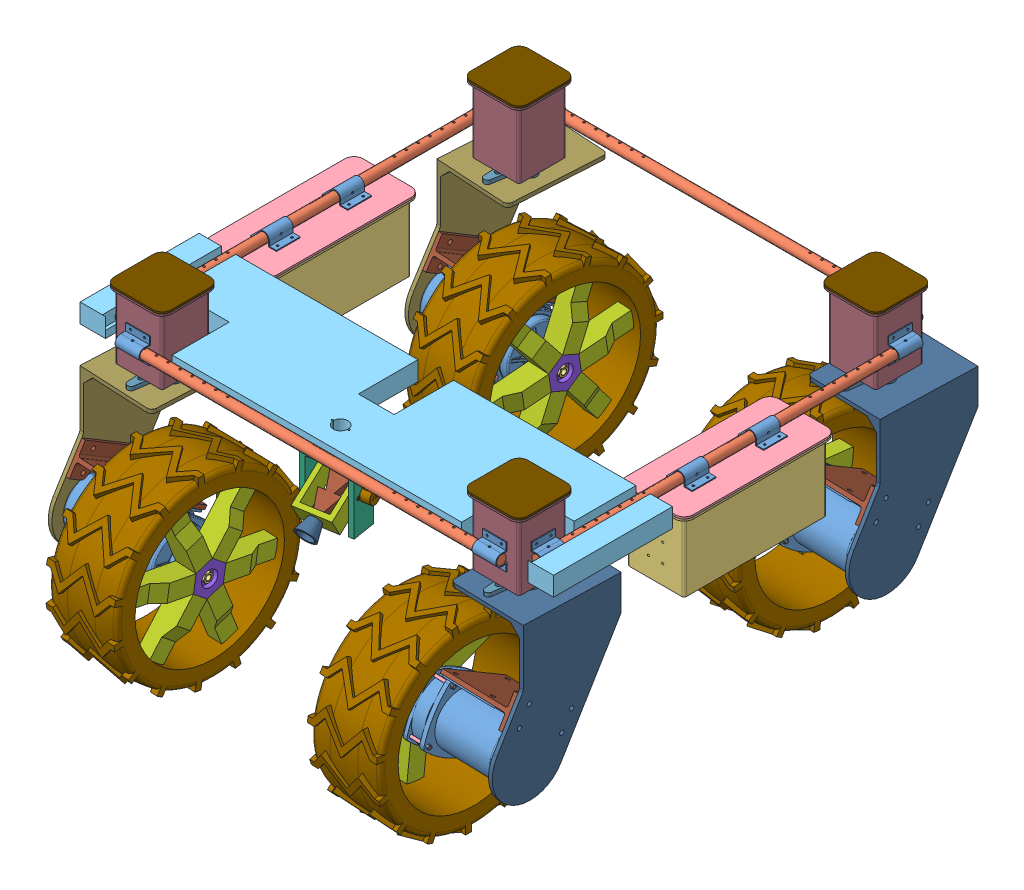
SolidWorks assembly base, configuration Default. Lengths in mm.
Overall size (1139.21 690.44 1393.09).
161 component instances, 29 part files, 89 mates.
Components (placement in the parent):
- movement_assem_L-2: movement_assem_L [Default] at (453.6293 -115.4019 95.0377) x (0.013657 -0.005104 0.999894) z (-0.999907 0 0.013657) size (528.97 522.15 293.99) (flexible)
  - 1020ZXF-36V_500W-1: 1020ZXF-36V_500W [Default] at (-85.1575 -185.5352 561.7867) x (-0.862659 -0.50441 -0.03729) z (-0.043058 -0.00022 0.999073) size (142 134 263.95)
    - 1020ZXF-36V_500W_Motor(Domyœlna_As Machined_)-1: 1020ZXF-36V_500W_Motor(Domyœlna_As Machined_) [Default] at origin size (142 134 246)
    - Chain wheel DIN 8192 - A 10Z 083-1: Chain wheel DIN 8192 - A 10Z 083 [Default] at (0 0 83.7384) x (0 0 -1) z (-0.648186 0.761482 0) size (6.02 48.2 49.22)
    - ISO 4034 - M12-1: ISO 4034 - M12 [Default] at (0 0 116.4471) x (0.997504 0.070613 0) z (0 0 1) size (18 20.78 10.2)
    - ISO 4017 - M6 x 50-1: ISO 4017 - M6 x 50 [Default] at (-50 50 40.5) x (0 0 -1) z (1 0 0) size (54 11.55 10)
    - ISO 4017 - M6 x 50-2: ISO 4017 - M6 x 50 [Default] at (50 50 40.5) x (0 0 -1) z (1 0 0) size (54 11.55 10)
    - ISO 4017 - M6 x 50-3: ISO 4017 - M6 x 50 [Default] at (50 -50 40.5) x (0 0 -1) z (1 0 0) size (54 11.55 10)
    - ISO 4017 - M6 x 50-4: ISO 4017 - M6 x 50 [Default] at (-50 -50 40.5) x (0 0 -1) z (1 0 0) size (54 11.55 10)
    - ISO 10511-M5-1: ISO 10511-M5 [Default] at (50 50 -11.45) x (0.923728 0.383049 0) z (0 0 -1) size (8 9.24 5)
    - ISO 10511-M5-2: ISO 10511-M5 [Default] at (-50 50 -11.45) x (0.923728 0.383049 0) z (0 0 -1) size (8 9.24 5)
    - ISO 10511-M5-3: ISO 10511-M5 [Default] at (-50 -50 -11.45) x (0.923728 0.383049 0) z (0 0 -1) size (8 9.24 5)
    - ISO 10511-M5-4: ISO 10511-M5 [Default] at (50 -50 -11.45) x (0.923728 0.383049 0) z (0 0 -1) size (8 9.24 5)
    - DIN 128 - A12-1: DIN 128 - A12 [Default] at (0 0 106.2471) x (0 0 1) z (-1 0 0) size (2.21 21.1 21.13)
  - wheel_assem-1: wheel_assem [Default] at (-131.3598 -177.1416 751.3131) x (-0.915563 0.400244 -0.039371) z (-0.043058 -0.00022 0.999073) size (397.67 396.05 151.27)
    - wheel_spoke-1: wheel_spoke [Default] at (-38.1992 -7.4775 -95.0997) x (0.866025 0.5 0) z (0 0 1) size (35 119.69 45)
    - wheel_hub-1: wheel_hub [Default] at (-38.1988 -7.4782 -95.0997) x (0.866025 0.5 0) z (0 0 1) size (70 60.62 45)
    - wheel_tire-1: wheel_tire [Default] at (-38.1988 182.5218 -147.5997) x (0 0 -1) z (1 0 0) size (151.27 396.05 397.67)
    - wheel_spoke-2: wheel_spoke [Default] at (-38.1997 -7.4782 -95.0997) x (0 1 0) z (0 0 1) size (35 119.69 45)
    - wheel_spoke-4: wheel_spoke [Default] at (-38.1992 -7.479 -95.0997) x (-0.866025 0.5 0) z (0 0 1) size (35 119.69 45)
    - wheel_spoke-6: wheel_spoke [Default] at (-38.1983 -7.479 -95.0997) x (-0.866025 -0.5 0) z (0 0 1) size (35 119.69 45)
    - wheel_spoke-8: wheel_spoke [Default] at (-38.1979 -7.4782 -95.0997) x (0 -1 0) z (0 0 1) size (35 119.69 45)
    - wheel_spoke-10: wheel_spoke [Default] at (-38.1983 -7.4775 -95.0997) x (0.866025 -0.5 0) z (0 0 1) size (35 119.69 45)
  - wheel_mount_L-1: wheel_mount_L [Default] at (-78.8064 -185.5028 414.4235) x (-0.99906 -0.005099 -0.043059) z (0.043058 0.00022 -0.999073) size (263.45 325 158)
  - motor_mount-1: motor_mount [Default] at (-182.1743 -168.1045 559.1107) x (0.043058 0.00022 -0.999073) z (0.862659 0.50441 0.03729) size (149 64 150)
- movement_assem_R-1: movement_assem_R [Default] at (308.36 139.153 246.9765) x (-0.802913 0.008146 -0.596041) z (0.59601 -0.006047 -0.802954) size (456.92 476.81 461.52) (flexible)
  - wheel_mount_R-1: wheel_mount_R [Default] at (1548.2344 -451.8258 76.5233) x (0.547057 0.000606 0.837095) z (-0.837055 0.010127 0.547024) size (263.45 325 158)
  - 1020ZXF-36V_500W-1: 1020ZXF-36V_500W [Default] at (1418.0723 -450.251 161.5856) x (-0.469693 0.49945 -0.727969) z (-0.837055 0.010127 0.547024) size (142 134 263.95)
    - 1020ZXF-36V_500W_Motor(Domyœlna_As Machined_)-1: 1020ZXF-36V_500W_Motor(Domyœlna_As Machined_) [Default] at origin size (142 134 246)
    - Chain wheel DIN 8192 - A 10Z 083-1: Chain wheel DIN 8192 - A 10Z 083 [Default] at (0 0 83.7384) x (0 0 -1) z (-0.648186 0.761482 0) size (6.02 48.2 49.22)
    - ISO 4034 - M12-1: ISO 4034 - M12 [Default] at (0 0 116.4471) x (0.997504 0.070613 0) z (0 0 1) size (18 20.78 10.2)
    - ISO 4017 - M6 x 50-1: ISO 4017 - M6 x 50 [Default] at (-50 50 40.5) x (0 0 -1) z (1 0 0) size (54 11.55 10)
    - ISO 4017 - M6 x 50-2: ISO 4017 - M6 x 50 [Default] at (50 50 40.5) x (0 0 -1) z (1 0 0) size (54 11.55 10)
    - ISO 4017 - M6 x 50-3: ISO 4017 - M6 x 50 [Default] at (50 -50 40.5) x (0 0 -1) z (1 0 0) size (54 11.55 10)
    - ISO 4017 - M6 x 50-4: ISO 4017 - M6 x 50 [Default] at (-50 -50 40.5) x (0 0 -1) z (1 0 0) size (54 11.55 10)
    - ISO 10511-M5-1: ISO 10511-M5 [Default] at (50 50 -11.45) x (0.923728 0.383049 0) z (0 0 -1) size (8 9.24 5)
    - ISO 10511-M5-2: ISO 10511-M5 [Default] at (-50 50 -11.45) x (0.923728 0.383049 0) z (0 0 -1) size (8 9.24 5)
    - ISO 10511-M5-3: ISO 10511-M5 [Default] at (-50 -50 -11.45) x (0.923728 0.383049 0) z (0 0 -1) size (8 9.24 5)
    - ISO 10511-M5-4: ISO 10511-M5 [Default] at (50 -50 -11.45) x (0.923728 0.383049 0) z (0 0 -1) size (8 9.24 5)
    - DIN 128 - A12-1: DIN 128 - A12 [Default] at (0 0 106.2471) x (0 0 1) z (-1 0 0) size (2.21 21.1 21.13)
  - wheel_assem-1: wheel_assem [Default] at (1278.1168 -435.4451 296.9317) x (0.542633 0.143128 0.827686) z (-0.837055 0.010127 0.547024) size (397.67 396.05 151.27)
    - wheel_spoke-1: wheel_spoke [Default] at (-38.1992 -7.4775 -95.0997) x (0.866025 0.5 0) z (0 0 1) size (35 119.69 45)
    - wheel_hub-1: wheel_hub [Default] at (-38.1988 -7.4782 -95.0997) x (0.866025 0.5 0) z (0 0 1) size (70 60.62 45)
    - wheel_tire-1: wheel_tire [Default] at (-38.1988 182.5218 -147.5997) x (0 0 -1) z (1 0 0) size (151.27 396.05 397.67)
    - wheel_spoke-2: wheel_spoke [Default] at (-38.1997 -7.4782 -95.0997) x (0 1 0) z (0 0 1) size (35 119.69 45)
    - wheel_spoke-4: wheel_spoke [Default] at (-38.1992 -7.479 -95.0997) x (-0.866025 0.5 0) z (0 0 1) size (35 119.69 45)
    - wheel_spoke-6: wheel_spoke [Default] at (-38.1983 -7.479 -95.0997) x (-0.866025 -0.5 0) z (0 0 1) size (35 119.69 45)
    - wheel_spoke-8: wheel_spoke [Default] at (-38.1979 -7.4782 -95.0997) x (0 -1 0) z (0 0 1) size (35 119.69 45)
    - wheel_spoke-10: wheel_spoke [Default] at (-38.1983 -7.4775 -95.0997) x (0.866025 -0.5 0) z (0 0 1) size (35 119.69 45)
  - motor_mount-1: motor_mount [Default] at (1399.5471 -357.3349 134.2603) x (0.837055 -0.010127 -0.547024) z (0.469693 -0.49945 0.727969) size (149 64 150)
- movement_assem_R-2: movement_assem_R [Default] at (1078.4309 131.34 212.064) x (-0.802913 0.008146 -0.596041) z (0.59601 -0.006047 -0.802954) size (462.42 474.36 458.54) (flexible)
  - wheel_mount_R-1: wheel_mount_R [Default] at (1697.4603 -451.8181 -1013.2261) x (0.556985 0.000485 0.830522) z (-0.830483 0.010134 0.556952) size (263.45 325 158)
  - 1020ZXF-36V_500W-1: 1020ZXF-36V_500W [Default] at (1568.3203 -450.2423 -926.62) x (-0.47829 0.499554 -0.722277) z (-0.830483 0.010134 0.556952) size (142 134 263.95)
    - 1020ZXF-36V_500W_Motor(Domyœlna_As Machined_)-1: 1020ZXF-36V_500W_Motor(Domyœlna_As Machined_) [Default] at origin size (142 134 246)
    - Chain wheel DIN 8192 - A 10Z 083-1: Chain wheel DIN 8192 - A 10Z 083 [Default] at (0 0 83.7384) x (0 0 -1) z (-0.648186 0.761482 0) size (6.02 48.2 49.22)
    - ISO 4034 - M12-1: ISO 4034 - M12 [Default] at (0 0 116.4471) x (0.997504 0.070613 0) z (0 0 1) size (18 20.78 10.2)
    - ISO 4017 - M6 x 50-1: ISO 4017 - M6 x 50 [Default] at (-50 50 40.5) x (0 0 -1) z (1 0 0) size (54 11.55 10)
    - ISO 4017 - M6 x 50-2: ISO 4017 - M6 x 50 [Default] at (50 50 40.5) x (0 0 -1) z (1 0 0) size (54 11.55 10)
    - ISO 4017 - M6 x 50-3: ISO 4017 - M6 x 50 [Default] at (50 -50 40.5) x (0 0 -1) z (1 0 0) size (54 11.55 10)
    - ISO 4017 - M6 x 50-4: ISO 4017 - M6 x 50 [Default] at (-50 -50 40.5) x (0 0 -1) z (1 0 0) size (54 11.55 10)
    - ISO 10511-M5-1: ISO 10511-M5 [Default] at (50 50 -11.45) x (0.923728 0.383049 0) z (0 0 -1) size (8 9.24 5)
    - ISO 10511-M5-2: ISO 10511-M5 [Default] at (-50 50 -11.45) x (0.923728 0.383049 0) z (0 0 -1) size (8 9.24 5)
    - ISO 10511-M5-3: ISO 10511-M5 [Default] at (-50 -50 -11.45) x (0.923728 0.383049 0) z (0 0 -1) size (8 9.24 5)
    - ISO 10511-M5-4: ISO 10511-M5 [Default] at (50 -50 -11.45) x (0.923728 0.383049 0) z (0 0 -1) size (8 9.24 5)
    - DIN 128 - A12-1: DIN 128 - A12 [Default] at (0 0 106.2471) x (0 0 1) z (-1 0 0) size (2.21 21.1 21.13)
  - wheel_assem-1: wheel_assem [Default] at (1387.7427 -449.9271 -852.3437) x (-0.549322 0.151008 -0.821853) z (-0.830483 0.010134 0.556952) size (397.67 396.05 151.27)
    - wheel_spoke-1: wheel_spoke [Default] at (-38.1992 -7.4775 -95.0997) x (0.866025 0.5 0) z (0 0 1) size (35 119.69 45)
    - wheel_hub-1: wheel_hub [Default] at (-38.1988 -7.4782 -95.0997) x (0.866025 0.5 0) z (0 0 1) size (70 60.62 45)
    - wheel_tire-1: wheel_tire [Default] at (-38.1988 182.5218 -147.5997) x (0 0 -1) z (1 0 0) size (151.27 396.05 397.67)
    - wheel_spoke-2: wheel_spoke [Default] at (-38.1997 -7.4782 -95.0997) x (0 1 0) z (0 0 1) size (35 119.69 45)
    - wheel_spoke-4: wheel_spoke [Default] at (-38.1992 -7.479 -95.0997) x (-0.866025 0.5 0) z (0 0 1) size (35 119.69 45)
    - wheel_spoke-6: wheel_spoke [Default] at (-38.1983 -7.479 -95.0997) x (-0.866025 -0.5 0) z (0 0 1) size (35 119.69 45)
    - wheel_spoke-8: wheel_spoke [Default] at (-38.1979 -7.4782 -95.0997) x (0 -1 0) z (0 0 1) size (35 119.69 45)
    - wheel_spoke-10: wheel_spoke [Default] at (-38.1983 -7.4775 -95.0997) x (0.866025 -0.5 0) z (0 0 1) size (35 119.69 45)
  - motor_mount-1: motor_mount [Default] at (1549.4778 -357.3223 -953.7138) x (0.830483 -0.010134 -0.556952) z (0.47829 -0.499554 0.722277) size (149 64 150)
- movement_assem_L-3: movement_assem_L [Default] at (-192.5085 -276.0842 -734.4233) x (-0.030361 0 0.999539) z (-0.999539 0 -0.030361) size (552.75 553.15 274.8) (flexible)
  - 1020ZXF-36V_500W-1: 1020ZXF-36V_500W [Default] at (-1.5479 -24.4158 -83.1555) x (-0.866025 -0.5 0) z (0 0 1) size (142 134 263.95)
    - 1020ZXF-36V_500W_Motor(Domyœlna_As Machined_)-1: 1020ZXF-36V_500W_Motor(Domyœlna_As Machined_) [Default] at origin size (142 134 246)
    - Chain wheel DIN 8192 - A 10Z 083-1: Chain wheel DIN 8192 - A 10Z 083 [Default] at (0 0 83.7384) x (0 0 -1) z (-0.648186 0.761482 0) size (6.02 48.2 49.22)
    - ISO 4034 - M12-1: ISO 4034 - M12 [Default] at (0 0 116.4471) x (0.997504 0.070613 0) z (0 0 1) size (18 20.78 10.2)
    - ISO 4017 - M6 x 50-1: ISO 4017 - M6 x 50 [Default] at (-50 50 40.5) x (0 0 -1) z (1 0 0) size (54 11.55 10)
    - ISO 4017 - M6 x 50-2: ISO 4017 - M6 x 50 [Default] at (50 50 40.5) x (0 0 -1) z (1 0 0) size (54 11.55 10)
    - ISO 4017 - M6 x 50-3: ISO 4017 - M6 x 50 [Default] at (50 -50 40.5) x (0 0 -1) z (1 0 0) size (54 11.55 10)
    - ISO 4017 - M6 x 50-4: ISO 4017 - M6 x 50 [Default] at (-50 -50 40.5) x (0 0 -1) z (1 0 0) size (54 11.55 10)
    - ISO 10511-M5-1: ISO 10511-M5 [Default] at (50 50 -11.45) x (0.923728 0.383049 0) z (0 0 -1) size (8 9.24 5)
    - ISO 10511-M5-2: ISO 10511-M5 [Default] at (-50 50 -11.45) x (0.923728 0.383049 0) z (0 0 -1) size (8 9.24 5)
    - ISO 10511-M5-3: ISO 10511-M5 [Default] at (-50 -50 -11.45) x (0.923728 0.383049 0) z (0 0 -1) size (8 9.24 5)
    - ISO 10511-M5-4: ISO 10511-M5 [Default] at (50 -50 -11.45) x (0.923728 0.383049 0) z (0 0 -1) size (8 9.24 5)
    - DIN 128 - A12-1: DIN 128 - A12 [Default] at (0 0 106.2471) x (0 0 1) z (-1 0 0) size (2.21 21.1 21.13)
  - wheel_assem-1: wheel_assem [Default] at (26.5517 -51.3506 108.1826) x (0.575515 -0.817791 0) z (0 0 1) size (397.67 396.05 151.27)
    - wheel_spoke-1: wheel_spoke [Default] at (-38.1992 -7.4775 -95.0997) x (0.866025 0.5 0) z (0 0 1) size (35 119.69 45)
    - wheel_hub-1: wheel_hub [Default] at (-38.1988 -7.4782 -95.0997) x (0.866025 0.5 0) z (0 0 1) size (70 60.62 45)
    - wheel_tire-1: wheel_tire [Default] at (-38.1988 182.5218 -147.5997) x (0 0 -1) z (1 0 0) size (151.27 396.05 397.67)
    - wheel_spoke-2: wheel_spoke [Default] at (-38.1997 -7.4782 -95.0997) x (0 1 0) z (0 0 1) size (35 119.69 45)
    - wheel_spoke-4: wheel_spoke [Default] at (-38.1992 -7.479 -95.0997) x (-0.866025 0.5 0) z (0 0 1) size (35 119.69 45)
    - wheel_spoke-6: wheel_spoke [Default] at (-38.1983 -7.479 -95.0997) x (-0.866025 -0.5 0) z (0 0 1) size (35 119.69 45)
    - wheel_spoke-8: wheel_spoke [Default] at (-38.1979 -7.4782 -95.0997) x (0 -1 0) z (0 0 1) size (35 119.69 45)
    - wheel_spoke-10: wheel_spoke [Default] at (-38.1983 -7.4775 -95.0997) x (0.866025 -0.5 0) z (0 0 1) size (35 119.69 45)
  - wheel_mount_L-1: wheel_mount_L [Default] at (-1.5479 -24.4158 -230.6555) x (-1 0 0) z (0 0 -1) size (263.45 325 158)
  - motor_mount-1: motor_mount [Default] at (-98.4998 -6.4902 -81.6555) x (0 0 -1) z (0.866025 0.5 0) size (149 64 150)
- steering_assem-1: steering_assem [Default] at (-795.7944 -34.5 -800) x (-1 0 0) z (0 0 -1) size (120 165 143.01) (flexible)
  - steering_box-1: steering_box [Default] at origin size (120 143 120)
  - stepper_mount-1: stepper_mount [Default] at (0 -12 0) x (0.059684 0 -0.998217) z (0.998217 0 0.059684) size (140 16 77.5)
  - steper-1: steper [Default] at (-94.8723 62.6664 -82.6717) x (0 -1 0) z (0 0 1) size (152 86 86)
    - back-1: back [Default] at (-71.3336 51.8723 125.6717) size (15 86 86)
    - coil-1: coil [Default] at (-56.3336 51.8723 125.6717) size (95 86 86)
    - front-1: front [Default] at (38.6664 51.8723 125.6717) size (42 86 86)
  - steering_box_lid-1: steering_box_lid [Default] at (-60 143 60) size (120 4 120)
- steering_assem-2: steering_assem [Default] at (-795.7944 -34.5 -50) x (0 0 1) z (-1 0 0) size (143.86 165 120) (flexible)
  - steering_box-1: steering_box [Default] at origin size (120 143 120)
  - stepper_mount-1: stepper_mount [Default] at (0 -12 0) x (0.998857 0 0.047794) z (-0.047794 0 0.998857) size (140 16 77.5)
  - steper-1: steper [Default] at (-94.8723 62.6664 -82.6717) x (0 -1 0) z (0 0 1) size (152 86 86)
    - back-1: back [Default] at (-71.3336 51.8723 125.6717) size (15 86 86)
    - coil-1: coil [Default] at (-56.3336 51.8723 125.6717) size (95 86 86)
    - front-1: front [Default] at (38.6664 51.8723 125.6717) size (42 86 86)
  - steering_box_lid-1: steering_box_lid [Default] at (-60 143 60) size (120 4 120)
- steering_assem-3: steering_assem [Default] at (-45.7944 -34.5 -800) x (0 0 -1) z (1 0 0) size (142.29 165 120) (flexible)
  - steering_box-1: steering_box [Default] at origin size (120 143 120)
  - stepper_mount-1: stepper_mount [Default] at (0 -12 0) x (-0.999539 0 -0.030361) z (0.030361 0 -0.999539) size (140 16 77.5)
  - steper-1: steper [Default] at (-94.8723 62.6664 -82.6717) x (0 -1 0) z (0 0 1) size (152 86 86)
    - back-1: back [Default] at (-71.3336 51.8723 125.6717) size (15 86 86)
    - coil-1: coil [Default] at (-56.3336 51.8723 125.6717) size (95 86 86)
    - front-1: front [Default] at (38.6664 51.8723 125.6717) size (42 86 86)
  - steering_box_lid-1: steering_box_lid [Default] at (-60 143 60) size (120 4 120)
- steering_assem-4: steering_assem [Default] at (-45.7944 -34.5 -50) size (120 165 142.22) (flexible)
  - steering_box-1: steering_box [Default] at origin size (120 143 120)
  - stepper_mount-1: stepper_mount [Default] at (0 -12 0) x (0.02941 0 -0.999567) z (0.999567 0 0.02941) size (140 16 77.5)
  - steper-1: steper [Default] at (-94.8723 62.6664 -82.6717) x (0 -1 0) z (0 0 1) size (152 86 86)
    - back-1: back [Default] at (-71.3336 51.8723 125.6717) size (15 86 86)
    - coil-1: coil [Default] at (-56.3336 51.8723 125.6717) size (95 86 86)
    - front-1: front [Default] at (38.6664 51.8723 125.6717) size (42 86 86)
  - steering_box_lid-1: steering_box_lid [Default] at (-60 143 60) size (120 4 120)
- C-clamp-9: C-clamp [Default] at (-20.7944 25 -862) x (0 0 1) z (-1 0 0) size (24 54 50)
- C-clamp-10: C-clamp [Default] at (16.2056 25 -775) x (-1 0 0) z (0 0 -1) size (24 54 50)
- C-clamp-12: C-clamp [Default] at (-770.7944 25 -862) x (0 0 1) z (-1 0 0) size (24 54 50)
- C-clamp-14: C-clamp [Default] at (-857.7944 25 -825) size (24 54 50)
- C-clamp-16: C-clamp [Default] at (-857.7944 25 -75) size (24 54 50)
- C-clamp-18: C-clamp [Default] at (-820.7944 25 12) x (0 0 -1) z (1 0 0) size (24 54 50)
- C-clamp-20: C-clamp [Default] at (16.2056 25 -25) x (-1 0 0) z (0 0 -1) size (24 54 50)
- C-clamp-22: C-clamp [Default] at (-70.7944 25 12) x (0 0 -1) z (1 0 0) size (24 54 50)
- base_rod-5: base_rod [Default] at (-857.7944 25 -25) x (-1 0 0) z (0 0 -1) size (20 20 800)
- base_rod-6: base_rod [Default] at (-20.7944 25 -862) x (0 0 1) z (-1 0 0) size (20 20 800)
- base_rod-7: base_rod [Default] at (16.2056 25 -25) x (1 0 0) z (0 0 -1) size (20 20 800)
- base_rod-10: base_rod [Default] at (-820.7944 25 12) x (0 0 1) z (1 0 0) size (20 20 800)
- battery_box-1: battery_box [Default] at (-857.7944 -139 -425) x (0 0 1) z (-1 0 0) size (320 148 140)
- battery_box_lid-1: battery_box_lid [Default] at (-787.7944 9 -585) x (-1 0 0) z (0 0 -1) size (140 4 320)
- battery_box-2: battery_box [Default] at (16.2056 -139 -425) x (0 0 1) z (-1 0 0) size (320 148 140)
- battery_box_lid-3: battery_box_lid [Default] at (86.2056 9 -585) x (-1 0 0) z (0 0 -1) size (140 4 320)
- C-clamp-24: C-clamp [Default] at (16.2056 25 -475) x (0 -1 0) z (0 0 -1) size (24 54 50)
- C-clamp-25: C-clamp [Default] at (16.2056 25 -325) x (0 -1 0) z (0 0 -1) size (24 54 50)
- C-clamp-27: C-clamp [Default] at (-857.7944 25 -325) x (0 -1 0) z (0 0 -1) size (24 54 50)
- C-clamp-29: C-clamp [Default] at (-857.7944 25 -475) x (0 -1 0) z (0 0 -1) size (24 54 50)
- base_plate-1: base_plate [Default] at (-726.5887 0 0) x (0 0 -1) z (1 0 0) size (250 40 995.15)
- Sprayer-Assembly-1: Sprayer-Assembly [Default] at (-413.4144 -2 -66.98) x (-1 0 0) z (0 0 -1) size (132.2 148.51 163.59) (flexible)
  - Sprayer-OuterPiece-1: Sprayer-OuterPiece [Default] at (7.38 -2 -25.48) x (0 1 0) z (0.98664 0 -0.162918) size (125 50 100)
  - Sprayer-InnerPiece-1: Sprayer-InnerPiece [Default] at (-1.3939 -96.216 -78.6153) x (0.140383 0.507456 0.850165) z (-0.98664 0 0.162918) size (125 40 98.1)
  - Sprayer-Outer-Motor-Connector-1: Sprayer-Outer-Motor-Connector [Default] at (7.38 -13 -25.48) x (0.989189 0 0.146647) z (-0.146647 0 0.989189) size (10 14 11.55)
  - 28BYJ-48-1: 28BYJ-48 [Varsayılan] at (-62.5727 -56 -13.9291) x (0.162918 0 0.98664) z (0 1 0) size (42 28.9 33.48)
  - 28BYJ-48-2: 28BYJ-48 [Varsayılan] at (7.38 18.9 -16.98) x (-1 0 0) z (0 0 1) size (42 28.9 33.48)
  - Sprayer-Nozzle-01-1: Sprayer-Nozzle-01 [Default] at (-1.3939 -96.216 -78.6153) x (0.140383 0.507456 0.850165) z (0.98833 -0.020548 -0.150933) size (30 41.08 41.08)
  - Sprayer-Junction-1: Sprayer-Junction [Default] at (8.0297 -97.604 -67.5805) x (0.140383 0.507456 0.850165) z (0.082674 -0.861678 0.500676) size (75 45 15)
Mates (geometry in assembly coordinates):
- Coincident20: coincident aligned: plane of movement_assem_R-1/wheel_mount_R-1 through (-886.4158 -50.5 -725.2754) normal (0 1 0); plane of movement_assem_R-2/wheel_mount_R-1 through (-885.5196 -50.5 25.7983) normal (0 1 0)
- Coincident21: coincident aligned: plane of movement_assem_L-2/wheel_mount_L-1 through (45.8121 -50.5 32.73) normal (0 1 0); plane of movement_assem_R-2/wheel_mount_R-1 through (-885.5196 -50.5 25.7983) normal (0 1 0)
- Coincident22: coincident aligned: plane of movement_assem_L-2/wheel_mount_L-1 through (45.8121 -50.5 32.73) normal (0 1 0); plane of movement_assem_L-3/wheel_mount_L-1 through (45.7334 -50.5 -717.1829) normal (0 1 0)
- Coincident50: coincident anti-aligned: plane of movement_assem_R-1/wheel_mount_R-1 through (-886.4158 -50.5 -725.2754) normal (0 1 0); plane of steering_assem-1/stepper_mount-1 through (-799.5246 -50.5 -737.6114) normal (0 -1 0)
- Coincident51: coincident anti-aligned: plane of movement_assem_R-2/wheel_mount_R-1 through (-885.5196 -50.5 25.7983) normal (0 1 0); plane of steering_assem-2/stepper_mount-1 through (-798.7815 -50.5 12.4286) normal (0 -1 0)
- Coincident52: coincident anti-aligned: plane of movement_assem_L-2/wheel_mount_L-1 through (45.8121 -50.5 32.73) normal (0 1 0); plane of steering_assem-4/stepper_mount-1 through (-43.9562 -50.5 -112.473) normal (0 -1 0)
- Coincident54: coincident anti-aligned: plane of steering_assem-3/steering_box-1 through (-95.7944 -30.5 -850) normal (0 0 -1); plane of C-clamp-9 through (-70.7944 15 -850) normal (0 0 1)
- Coincident55: coincident anti-aligned: plane of steering_assem-3/steering_box-1 through (4.2056 -30.5 -750) normal (1 0 0); plane of C-clamp-10 through (4.2056 15 -825) normal (-1 0 0)
- Coincident56: coincident anti-aligned: plane of steering_assem-1/steering_box-1 through (-745.7944 -30.5 -850) normal (0 0 -1); plane of C-clamp-12 through (-820.7944 15 -850) normal (0 0 1)
- Coincident57: coincident anti-aligned: plane of steering_assem-1/steering_box-1 through (-845.7944 -30.5 -750) normal (-1 0 0); plane of C-clamp-14 through (-845.7944 15 -775) normal (1 0 0)
- Coincident58: coincident anti-aligned: plane of steering_assem-2/steering_box-1 through (-845.7944 -30.5 -100) normal (-1 0 0); plane of C-clamp-16 through (-845.7944 15 -25) normal (1 0 0)
- Coincident59: coincident anti-aligned: plane of steering_assem-2/steering_box-1 through (-745.7944 -30.5 0) normal (0 0 1); plane of C-clamp-18 through (-770.7944 15 0) normal (0 0 -1)
- Coincident60: coincident anti-aligned: plane of steering_assem-4/steering_box-1 through (4.2056 -30.5 -100) normal (1 0 0); plane of C-clamp-20 through (4.2056 15 -75) normal (-1 0 0)
- Coincident61: coincident anti-aligned: plane of steering_assem-4/steering_box-1 through (-95.7944 -30.5 0) normal (0 0 1); plane of C-clamp-22 through (-20.7944 15 0) normal (0 0 -1)
- Coincident69: coincident aligned: plane of battery_box-2 through (-53.7944 9 -284) normal (-1 0 0); plane of battery_box_lid-3 through (-53.7944 13 -585) normal (-1 0 0)
- Coincident68: coincident aligned: plane of battery_box-2 through (-34.7944 9 -585) normal (0 0 -1); plane of battery_box_lid-3 through (86.2056 13 -585) normal (0 0 -1)
- Coincident67: coincident anti-aligned: plane of battery_box-2 through (67.2056 9 -566) normal (0 1 0); plane of battery_box_lid-3 through (86.2056 9 -585) normal (0 -1 0)
- Coincident64: coincident aligned: plane of battery_box-1 through (-908.7944 9 -585) normal (0 0 -1); plane of battery_box_lid-1 through (-787.7944 13 -585) normal (0 0 -1)
- Coincident63: coincident aligned: plane of battery_box-1 through (-927.7944 9 -284) normal (-1 0 0); plane of battery_box_lid-1 through (-927.7944 13 -585) normal (-1 0 0)
- Coincident62: coincident anti-aligned: plane of battery_box-1 through (-806.7944 9 -566) normal (0 1 0); plane of battery_box_lid-1 through (-787.7944 9 -585) normal (0 -1 0)
- Coincident70: coincident anti-aligned: plane of battery_box_lid-3 through (86.2056 13 -585) normal (0 1 0); plane of C-clamp-24 through (26.2056 13 -525) normal (0 -1 0)
- Coincident79: coincident aligned: plane of base_plate-1 through (0 15 -250) normal (1 0 0)
- Coincident80: coincident anti-aligned: plane of base_plate-1 through (16.2056 0 -250) normal (0 -1 0)
- Coincident78: coincident aligned: plane of base_plate-1 through (-725 40 0) normal (0 0 1)
- Coincident73: coincident anti-aligned: plane of battery_box_lid-1 through (-787.7944 13 -585) normal (0 1 0); plane of C-clamp-29 through (-847.7944 13 -525) normal (0 -1 0)
- Coincident72: coincident anti-aligned: plane of battery_box_lid-1 through (-787.7944 13 -585) normal (0 1 0); plane of C-clamp-27 through (-847.7944 13 -375) normal (0 -1 0)
- Coincident71: coincident anti-aligned: plane of battery_box_lid-3 through (86.2056 13 -585) normal (0 1 0); plane of C-clamp-25 through (26.2056 13 -375) normal (0 -1 0)
- Coincident74: coincident aligned: plane of battery_box-1 through (-797.7944 -135 -575) normal (0 0 -1); plane of battery_box-2 through (76.2056 -135 -575) normal (0 0 -1)
- Concentric18: concentric aligned: cylinder of movement_assem_R-1/wheel_mount_R-1 through (-798.3309 -375.501 -757.5758) axis (0 1 0) radius 5; cylinder of steering_assem-1/stepper_mount-1 through (-798.3309 -50.5 -757.5758) axis (0 1 0) radius 5
- Concentric21: concentric aligned: cylinder of movement_assem_R-1/wheel_mount_R-1 through (-793.2578 -375.501 -842.4242) axis (0 1 0) radius 5; cylinder of steering_assem-1/stepper_mount-1 through (-793.2578 -50.5 -842.4242) axis (0 1 0) radius 5
- Concentric22: concentric aligned: cylinder of movement_assem_R-2/wheel_mount_R-1 through (-793.7631 -375.501 -92.4514) axis (0 1 0) radius 5; cylinder of steering_assem-2/stepper_mount-1 through (-793.7631 -50.5 -92.4514) axis (0 1 0) radius 5
- Concentric23: concentric aligned: cylinder of movement_assem_R-2/wheel_mount_R-1 through (-797.8256 -375.501 -7.5486) axis (0 1 0) radius 5; cylinder of steering_assem-2/stepper_mount-1 through (-797.8256 -50.5 -7.5486) axis (0 1 0) radius 5
- Concentric24: concentric aligned: cylinder of movement_assem_L-2/wheel_mount_L-1 through (-44.5444 -375.501 -92.4816) axis (0 1 0) radius 5; cylinder of steering_assem-4/stepper_mount-1 through (-44.5444 -50.5 -92.4816) axis (0 1 0) radius 5
- Concentric25: concentric aligned: cylinder of movement_assem_L-2/wheel_mount_L-1 through (-47.0443 -375.501 -7.5184) axis (0 1 0) radius 5; cylinder of steering_assem-4/stepper_mount-1 through (-47.0443 -50.5 -7.5184) axis (0 1 0) radius 5
- Concentric28: concentric aligned: cylinder of steering_assem-3/steering_box-1 through (-30.7944 44.5 -739.999) axis (0 0 -1) radius 2.25; cylinder of C-clamp-9 through (-30.7944 44.5 -849.999) axis (0 0 -1) radius 2.25
- Concentric29: concentric aligned: cylinder of steering_assem-3/steering_box-1 through (-60.7944 44.5 -739.999) axis (0 0 -1) radius 2.25; cylinder of C-clamp-9 through (-60.7944 44.5 -849.999) axis (0 0 -1) radius 2.25
- Concentric30: concentric aligned: cylinder of steering_assem-3/steering_box-1 through (-105.7954 44.5 -785) axis (1 0 0) radius 2.25; cylinder of C-clamp-10 through (4.2046 44.5 -785) axis (1 0 0) radius 2.25
- Concentric31: concentric aligned: cylinder of steering_assem-3/steering_box-1 through (-105.7954 44.5 -815) axis (1 0 0) radius 2.25; cylinder of C-clamp-10 through (4.2046 44.5 -815) axis (1 0 0) radius 2.25
- Concentric32: concentric aligned: cylinder of steering_assem-1/steering_box-1 through (-780.7944 44.5 -739.999) axis (0 0 -1) radius 2.25; cylinder of C-clamp-12 through (-780.7944 44.5 -849.999) axis (0 0 -1) radius 2.25
- Concentric33: concentric aligned: cylinder of steering_assem-1/steering_box-1 through (-810.7944 44.5 -739.999) axis (0 0 -1) radius 2.25; cylinder of C-clamp-12 through (-810.7944 44.5 -849.999) axis (0 0 -1) radius 2.25
- Concentric34: concentric aligned: cylinder of steering_assem-1/steering_box-1 through (-735.7934 44.5 -815) axis (-1 0 0) radius 2.25; cylinder of C-clamp-14 through (-845.7934 44.5 -815) axis (-1 0 0) radius 2.25
- Concentric35: concentric aligned: cylinder of steering_assem-1/steering_box-1 through (-735.7934 44.5 -785) axis (-1 0 0) radius 2.25; cylinder of C-clamp-14 through (-845.7934 44.5 -785) axis (-1 0 0) radius 2.25
- Concentric36: concentric aligned: cylinder of steering_assem-2/steering_box-1 through (-735.7934 44.5 -65) axis (-1 0 0) radius 2.25; cylinder of C-clamp-16 through (-845.7934 44.5 -65) axis (-1 0 0) radius 2.25
- Concentric37: concentric aligned: cylinder of steering_assem-2/steering_box-1 through (-735.7934 44.5 -35) axis (-1 0 0) radius 2.25; cylinder of C-clamp-16 through (-845.7934 44.5 -35) axis (-1 0 0) radius 2.25
- Concentric38: concentric aligned: cylinder of steering_assem-2/steering_box-1 through (-810.7944 44.5 -110.001) axis (0 0 1) radius 2.25; cylinder of C-clamp-18 through (-810.7944 44.5 -0.001) axis (0 0 1) radius 2.25
- Concentric39: concentric aligned: cylinder of steering_assem-2/steering_box-1 through (-780.7944 44.5 -110.001) axis (0 0 1) radius 2.25; cylinder of C-clamp-18 through (-780.7944 44.5 -0.001) axis (0 0 1) radius 2.25
- Concentric40: concentric aligned: cylinder of steering_assem-4/steering_box-1 through (-105.7954 44.5 -35) axis (1 0 0) radius 2.25; cylinder of C-clamp-20 through (4.2046 44.5 -35) axis (1 0 0) radius 2.25
- Concentric41: concentric aligned: cylinder of steering_assem-4/steering_box-1 through (-105.7954 44.5 -65) axis (1 0 0) radius 2.25; cylinder of C-clamp-20 through (4.2046 44.5 -65) axis (1 0 0) radius 2.25
- Concentric42: concentric aligned: cylinder of steering_assem-4/steering_box-1 through (-60.7944 44.5 -110.001) axis (0 0 1) radius 2.25; cylinder of C-clamp-22 through (-60.7944 44.5 -0.001) axis (0 0 1) radius 2.25
- Concentric43: concentric aligned: cylinder of steering_assem-4/steering_box-1 through (-30.7944 44.5 -110.001) axis (0 0 1) radius 2.25; cylinder of C-clamp-22 through (-30.7944 44.5 -0.001) axis (0 0 1) radius 2.25
- Concentric45: concentric anti-aligned: cylinder of C-clamp-16 through (-857.7944 25 -25) axis (0 0 -1) radius 10; cylinder of base_rod-5 through (-857.7944 25 -825) axis (0 0 1) radius 10
- Concentric46: concentric anti-aligned: cylinder of C-clamp-14 through (-857.7944 25 -775) axis (0 0 -1) radius 10; cylinder of base_rod-5 through (-857.7944 25 -825) axis (0 0 1) radius 10
- Concentric47: concentric aligned: cylinder of C-clamp-12 through (-820.7944 25 -862) axis (1 0 0) radius 10; cylinder of base_rod-6 through (-820.7944 25 -862) axis (1 0 0) radius 10
- Concentric49: concentric aligned: cylinder of C-clamp-9 through (-70.7944 25 -862) axis (1 0 0) radius 10; cylinder of base_rod-6 through (-820.7944 25 -862) axis (1 0 0) radius 10
- Concentric50: concentric aligned: cylinder of C-clamp-10 through (16.2056 25 -825) axis (0 0 1) radius 10; cylinder of base_rod-7 through (16.2056 25 -825) axis (0 0 1) radius 10
- Concentric51: concentric aligned: cylinder of C-clamp-20 through (16.2056 25 -75) axis (0 0 1) radius 10; cylinder of base_rod-7 through (16.2056 25 -825) axis (0 0 1) radius 10
- Concentric53: concentric aligned: cylinder of C-clamp-22 through (-20.7944 25 12) axis (-1 0 0) radius 10; cylinder of base_rod-10 through (-20.7944 25 12) axis (-1 0 0) radius 10
- Concentric54: concentric aligned: cylinder of C-clamp-18 through (-770.7944 25 12) axis (-1 0 0) radius 10; cylinder of base_rod-10 through (-20.7944 25 12) axis (-1 0 0) radius 10
- Concentric55: concentric aligned: cylinder of C-clamp-20 through (16.2056 6.636 -50) axis (0 1 0) radius 2.25; cylinder of base_rod-7 through (16.2056 14.999 -50) axis (0 1 0) radius 2.25
- Concentric56: concentric aligned: cylinder of C-clamp-22 through (-45.7944 6.636 12) axis (0 1 0) radius 2.25; cylinder of base_rod-10 through (-45.7944 14.999 12) axis (0 1 0) radius 2.25
- Concentric57: concentric aligned: cylinder of C-clamp-18 through (-795.7944 6.636 12) axis (0 1 0) radius 2.25; cylinder of base_rod-10 through (-795.7944 14.999 12) axis (0 1 0) radius 2.25
- Concentric58: concentric aligned: cylinder of C-clamp-10 through (16.2056 6.636 -800) axis (0 1 0) radius 2.25; cylinder of base_rod-7 through (16.2056 14.999 -800) axis (0 1 0) radius 2.25
- Concentric59: concentric anti-aligned: cylinder of C-clamp-12 through (-795.7944 6.636 -862) axis (0 1 0) radius 2.25; cylinder of base_rod-6 through (-795.7944 35.001 -862) axis (0 -1 0) radius 2.25
- Concentric60: concentric anti-aligned: cylinder of C-clamp-16 through (-857.7944 6.636 -50) axis (0 1 0) radius 2.25; cylinder of base_rod-5 through (-857.7944 35.001 -50) axis (0 -1 0) radius 2.25
- Concentric61: concentric aligned: cylinder of base_rod-7 through (16.2056 25 -825) axis (0 0 1) radius 10; cylinder of C-clamp-24 through (16.2056 25 -525) axis (0 0 1) radius 10
- Concentric62: concentric aligned: cylinder of battery_box_lid-3 through (35.7056 8.999 -485) axis (0 1 0) radius 2.25; cylinder of C-clamp-24 through (35.7056 12.999 -485) axis (0 1 0) radius 2.25
- Concentric63: concentric aligned: cylinder of battery_box_lid-3 through (35.7056 8.999 -515) axis (0 1 0) radius 2.25; cylinder of C-clamp-24 through (35.7056 12.999 -515) axis (0 1 0) radius 2.25
- Concentric64: concentric aligned: cylinder of base_rod-7 through (16.2056 25 -825) axis (0 0 1) radius 10; cylinder of C-clamp-25 through (16.2056 25 -375) axis (0 0 1) radius 10
- Concentric65: concentric aligned: cylinder of battery_box_lid-3 through (35.7056 8.999 -335) axis (0 1 0) radius 2.25; cylinder of C-clamp-25 through (35.7056 12.999 -335) axis (0 1 0) radius 2.25
- Concentric66: concentric aligned: cylinder of battery_box_lid-3 through (35.7056 8.999 -365) axis (0 1 0) radius 2.25; cylinder of C-clamp-25 through (35.7056 12.999 -365) axis (0 1 0) radius 2.25
- Concentric67: concentric aligned: cylinder of base_rod-5 through (-857.7944 25 -825) axis (0 0 1) radius 10; cylinder of C-clamp-27 through (-857.7944 25 -375) axis (0 0 1) radius 10
- Concentric69: concentric aligned: cylinder of battery_box_lid-1 through (-838.2944 8.999 -365) axis (0 1 0) radius 2.25; cylinder of C-clamp-27 through (-838.2944 12.999 -365) axis (0 1 0) radius 2.25
- Concentric70: concentric aligned: cylinder of battery_box_lid-1 through (-838.2944 8.999 -335) axis (0 1 0) radius 2.25; cylinder of C-clamp-27 through (-838.2944 12.999 -335) axis (0 1 0) radius 2.25
- Concentric71: concentric aligned: cylinder of battery_box_lid-1 through (-838.2944 8.999 -365) axis (0 1 0) radius 2.25; cylinder of C-clamp-27 through (-838.2944 12.999 -365) axis (0 1 0) radius 2.25
- Concentric72: concentric aligned: cylinder of base_rod-5 through (-857.7944 25 -825) axis (0 0 1) radius 10; cylinder of C-clamp-29 through (-857.7944 25 -525) axis (0 0 1) radius 10
- Concentric73: concentric aligned: cylinder of battery_box_lid-1 through (-838.2944 8.999 -485) axis (0 1 0) radius 2.25; cylinder of C-clamp-29 through (-838.2944 12.999 -485) axis (0 1 0) radius 2.25
- Concentric76: concentric aligned: cylinder of battery_box_lid-1 through (-838.2944 8.999 -515) axis (0 1 0) radius 2.25; cylinder of C-clamp-29 through (-838.2944 12.999 -515) axis (0 1 0) radius 2.25
- Concentric78: concentric anti-aligned: cylinder of base_plate-1 through (-403.2944 40 -50) axis (0 -1 0) radius 2; cylinder of Sprayer-Assembly-1/28BYJ-48-2 through (-403.2944 -2 -50) axis (0 1 0) radius 2
- Concentric77: concentric anti-aligned: cylinder of base_plate-1 through (-438.2944 40 -50) axis (0 -1 0) radius 2.0687; cylinder of Sprayer-Assembly-1/28BYJ-48-2 through (-438.2944 -2 -50) axis (0 1 0) radius 2
- Concentric79: concentric aligned: cylinder of base_rod-5 through (-857.7944 35.001 -250) axis (0 -1 0) radius 2.25; cylinder of base_plate-1 through (-857.7944 40 -250) axis (0 -1 0) radius 2.25
- Concentric80: concentric anti-aligned: cylinder of base_rod-7 through (16.2056 14.999 -250) axis (0 1 0) radius 2.25; cylinder of base_plate-1 through (16.2056 40 -250) axis (0 -1 0) radius 2.25
- Concentric85: concentric aligned: cylinder of movement_assem_L-3/wheel_mount_L-1 through (-44.504 -375.501 -842.4804) axis (0 1 0) radius 5; cylinder of steering_assem-3/stepper_mount-1 through (-44.504 -50.5 -842.4804) axis (0 1 0) radius 5
- Concentric84: concentric aligned: cylinder of movement_assem_L-3/wheel_mount_L-1 through (-47.0847 -375.501 -757.5196) axis (0 1 0) radius 5; cylinder of steering_assem-3/stepper_mount-1 through (-47.0847 -50.5 -757.5196) axis (0 1 0) radius 5
- Distance1: distance = 1 mm anti-aligned: plane of Sprayer-Assembly-1/28BYJ-48-2 through (-438.4044 -1 -50.01) normal (0 1 0); plane of base_plate-1 through (16.2056 0 -250) normal (0 -1 0)
- Parallel20: parallel aligned: plane of movement_assem_L-3/wheel_mount_L-1 through (45.7334 -50.5 -717.1829) normal (0 1 0)
- Parallel22: parallel aligned: plane of movement_assem_R-1/wheel_mount_R-1 through (-886.4158 -50.5 -725.2754) normal (0 1 0); plane of battery_box_lid-1 through (-787.7944 13 -585) normal (0 1 0)
- Parallel23: parallel aligned: plane of movement_assem_L-3/wheel_mount_L-1 through (45.7334 -50.5 -717.1829) normal (0 1 0); plane of battery_box_lid-3 through (86.2056 13 -585) normal (0 1 0)
- Tangent2: tangent anti-aligned: cylinder of base_rod-5 through (-857.7944 25 -825) axis (0 0 1) radius 10; plane of base_plate-1 through (-726.5887 15 0) normal (0 1 0)
- Width1: width anti-aligned: plane of battery_box-2 through (76.2056 -135 -575) normal (0 0 -1); plane of battery_box-2 through (76.2056 -135 -275) normal (0 0 1); plane of steering_assem-3/steering_box-1 through (-95.7944 -30.5 -750) normal (0 0 1); plane of steering_assem-4/steering_box-1 through (-95.7944 -30.5 -100) normal (0 0 -1)
